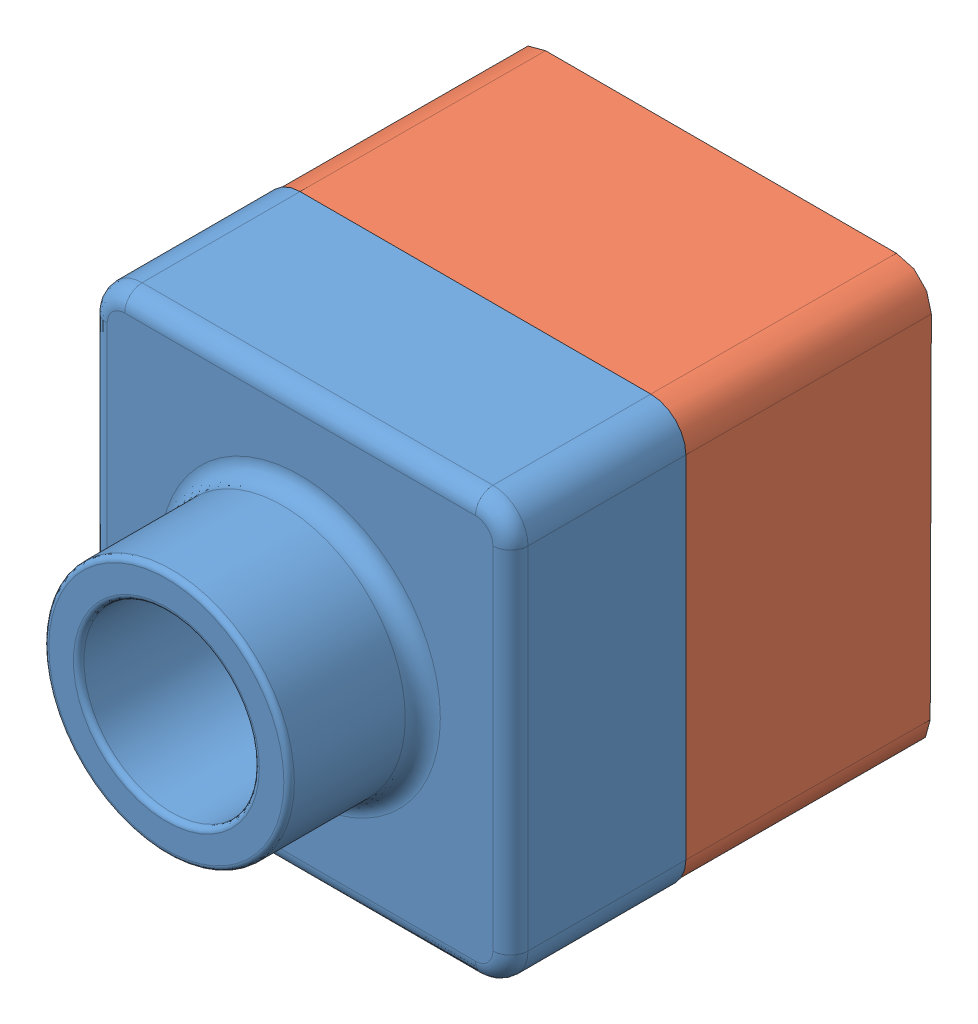
SolidWorks assembly Assemly1_2, configuration Default. Lengths in mm.
Overall size (120 120.29 158.1).
2 component instances, 2 part files, 1 mates.
Components (placement in the parent):
- Lesson1-2: Lesson1 [Default] at (-55.519 5.0063 74.2628) size (120 120 88.1)
- Lesson2-2: Lesson2 [Default] at (-55.519 4.7816 4.6494) x (1 0 0) z (0 0.003218 0.999995) size (120 120 90)
Mates (geometry in assembly coordinates):
- Coincident2: coincident aligned: line of Lesson1-2 through (54.481 125.0063 74.2628) axis (-1 0 0); line of Lesson2-2 through (54.481 125.0063 74.2628) axis (-1 0 0)
